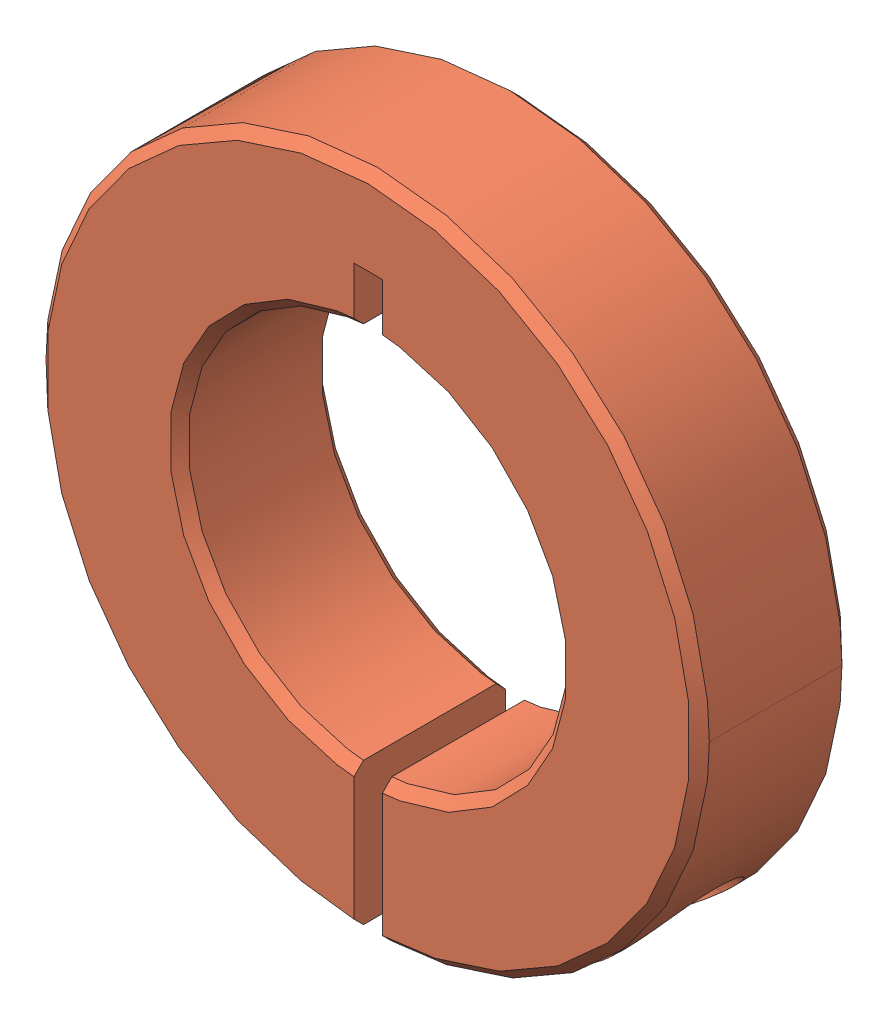
SolidWorks assembly SCSJ20_8, configuration Default. Lengths in mm.
Overall size (35 34.98 8).
2 component instances, 2 part files, 0 mates.
Components (placement in the parent):
- SCSJ20_8_3-1: SCSJ20_8_3 [Default] at (5 -13 0) x (-1 0 0) z (0 0 1) size (13 5.5 5.5)
- SCSJ20_8_5-1: SCSJ20_8_5 [Default] at origin size (35 34.98 8)
